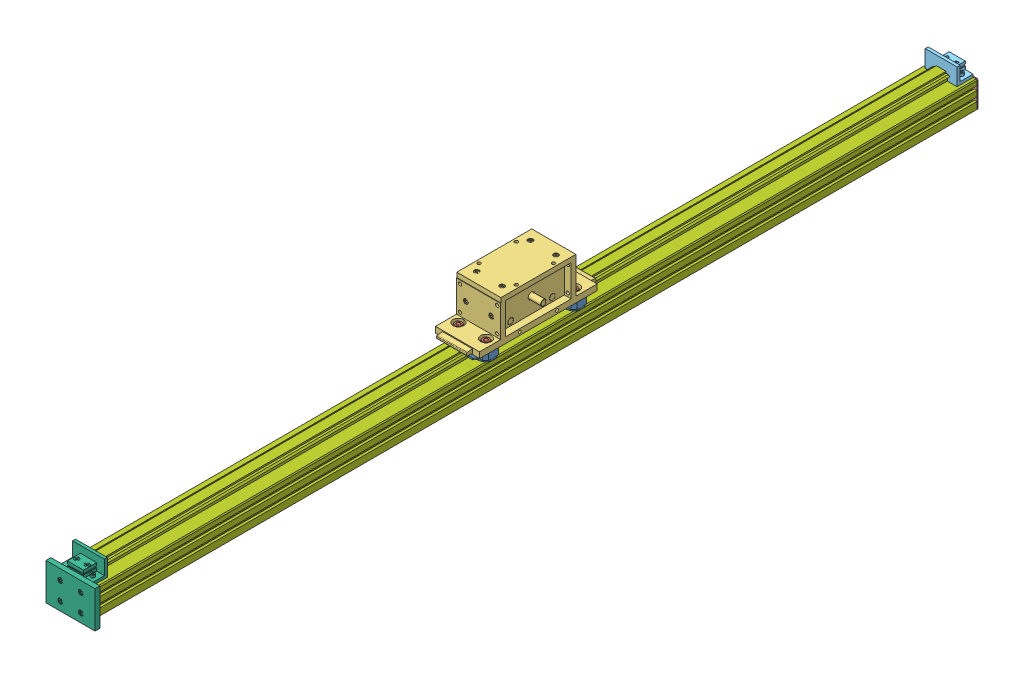
SolidWorks assembly DLS3C1800KKR_(735,0), configuration Default. Lengths in mm.
Overall size (112.01 170.3 1813.35).
13 component instances, 7 part files, 0 mates.
Components (placement in the parent):
- DLS3C_CS-1: DLS3C_CS [Default] at (-28.2 74.3 -809.8) x (0 0 1) z (1 0 0) size (55 20.9 30)
- DLS3C_SJ25C-1: DLS3C_SJ25C [Default] at (-28.2 74.3 -809.8) x (1 0 0) z (0 0 -1) size (25 26.61 25)
- DLS3C_CS-2: DLS3C_CS [Default] at (-28.2 74.3 -989.8) x (0 0 1) z (1 0 0) size (55 20.9 30)
- DLS3C_SJ25C-2: DLS3C_SJ25C [Default] at (-28.2 74.3 -989.8) x (1 0 0) z (0 0 -1) size (25 26.61 25)
- DLS3C_CS-3: DLS3C_CS [Default] at (28.2 74.3 -809.8) x (0 0 -1) z (-1 0 0) size (55 20.9 30)
- DLS3C_SJ25C-3: DLS3C_SJ25C [Default] at (28.2 74.3 -809.8) x (1 0 0) z (0 0 -1) size (25 26.61 25)
- DLS3C_CS-4: DLS3C_CS [Default] at (28.2 74.3 -989.8) x (0 0 -1) z (-1 0 0) size (55 20.9 30)
- DLS3C_SJ25C-4: DLS3C_SJ25C [Default] at (28.2 74.3 -989.8) x (1 0 0) z (0 0 -1) size (25 26.61 25)
- DLS3CKKR_C-1: DLS3CKKR_C [Default] at (0 74.3 -899.8) size (112.01 86 264)
- DLS3C_C-1: DLS3C_C [Default] at (0 27.5 -1800) x (0 0 -1) z (-1 0 0) size (3.35 55 80)
- DLS3C_B2-1: DLS3C_B2 [Default] at (0 0 -1799.6) x (-1 0 0) z (0 0 -1) size (65 45 32.8)
- DLS3C_B-1: DLS3C_B [Default] at origin size (100 100 42.8)
- DLS3C1800_(735)_B-1: DLS3C1800_(735)_B [Default] at origin size (80 70.95 1800)
